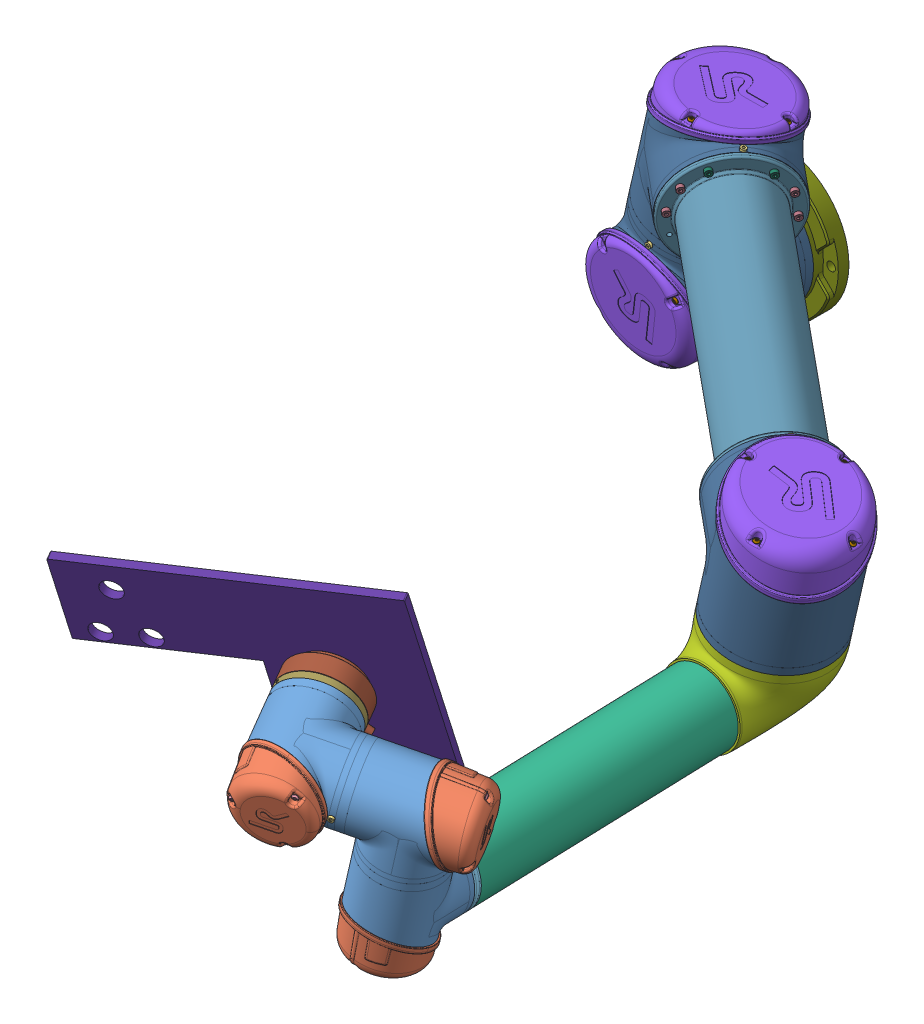
SolidWorks assembly 1-UR5-assembled, configuration Default. Lengths in mm.
75 component instances, 17 part files, 16 mates.
Components (placement in the parent):
- 1-Simple_Size 1_Joint_r01-1: 1-Simple_Size 1_Joint_r01 [默认] at (363.7688 30.1898 739.873) x (-0.221459 -0.97517 0) z (0.447518 -0.10163 0.888481) size (85.27 106.15 80.04)
  - 1-Size 1_House_r15_Simple-1: 1-Size 1_House_r15_Simple [默认] at origin size (82.75 89.23 75.23)
  - 1-Size 1_Joint lid_r08_Simple-1: 1-Size 1_Joint lid_r08_Simple [默认] at (0 -0.55 0) size (80.04 49.84 80.04)
  - 1-ISO 14580_M3x6_Torx_Rustfri A2_1-1: 1-ISO 14580_M3x6_Torx_Rustfri A2_1 [默认] at (42.25 40 0) x (0 -1 0) z (0 0 1) size (8.4 5.5 5.5)
  - 1-DIN 7985 Torx M3_DIN 7985 Torx M3 x 6 Syrefast-1: 1-DIN 7985 Torx M3_DIN 7985 Torx M3 x 6 Syrefast [默认] at (15.5 51.45 -26.8468) x (0 -1 0) z (0 0 1) size (7.97 5.77 5.75)
  - 1-DIN 7985 Torx M3_DIN 7985 Torx M3 x 6 Syrefast-2: 1-DIN 7985 Torx M3_DIN 7985 Torx M3 x 6 Syrefast [默认] at (15.5 51.45 26.8468) x (0 -1 0) z (0 0 1) size (7.97 5.77 5.75)
  - 1-DIN 7985 Torx M3_DIN 7985 Torx M3 x 6 Syrefast-3: 1-DIN 7985 Torx M3_DIN 7985 Torx M3 x 6 Syrefast [默认] at (-31 51.45 0) x (0 -1 0) z (0 0 1) size (7.97 5.77 5.75)
- 1-Simple_Size 1_Joint_r01-2: 1-Simple_Size 1_Joint_r01 [默认] at (281.6755 48.833 783.3551) x (0.86642 -0.196762 -0.458913) z (-0.290399 -0.946226 -0.142567) size (85.27 106.15 80.04)
  - 1-Size 1_House_r15_Simple-1: 1-Size 1_House_r15_Simple [默认] at origin size (82.75 89.23 75.23)
  - 1-Size 1_Joint lid_r08_Simple-1: 1-Size 1_Joint lid_r08_Simple [默认] at (0 -0.55 0) size (80.04 49.84 80.04)
  - 1-ISO 14580_M3x6_Torx_Rustfri A2_1-1: 1-ISO 14580_M3x6_Torx_Rustfri A2_1 [默认] at (42.25 40 0) x (0 -1 0) z (0 0 1) size (8.4 5.5 5.5)
  - 1-DIN 7985 Torx M3_DIN 7985 Torx M3 x 6 Syrefast-1: 1-DIN 7985 Torx M3_DIN 7985 Torx M3 x 6 Syrefast [默认] at (15.5 51.45 -26.8468) x (0 -1 0) z (0 0 1) size (7.97 5.77 5.75)
  - 1-DIN 7985 Torx M3_DIN 7985 Torx M3 x 6 Syrefast-2: 1-DIN 7985 Torx M3_DIN 7985 Torx M3 x 6 Syrefast [默认] at (15.5 51.45 26.8468) x (0 -1 0) z (0 0 1) size (7.97 5.77 5.75)
  - 1-DIN 7985 Torx M3_DIN 7985 Torx M3 x 6 Syrefast-3: 1-DIN 7985 Torx M3_DIN 7985 Torx M3 x 6 Syrefast [默认] at (-31 51.45 0) x (0 -1 0) z (0 0 1) size (7.97 5.77 5.75)
- 1-Simple_Underarm_r00-1: 1-Simple_Underarm_r00 [默认] at (332.2947 -59.8251 347.7706) x (-0.026745 0.006074 -0.999624) z (-0.974803 0.221376 0.027426) size (490.28 107.7 116.02)
  - 1-Adapter_Size 1 Tube to Female Size 1_r04_Simple-1: 1-Adapter_Size 1 Tube to Female Size 1_r04_Simple [默认] at (-345 0 0) x (-1 0 0) z (0 -0.876607 -0.481207) size (7 75 75)
  - 1-Simple_Size 1_Joint_r01-1: 1-Simple_Size 1_Joint_r01 [默认] at (-392.25 0 0) size (85.27 106.15 80.04)
    - 1-Size 1_House_r15_Simple-1: 1-Size 1_House_r15_Simple [默认] at origin size (82.75 89.23 75.23)
    - 1-Size 1_Joint lid_r08_Simple-1: 1-Size 1_Joint lid_r08_Simple [默认] at (0 -0.55 0) size (80.04 49.84 80.04)
    - 1-ISO 14580_M3x6_Torx_Rustfri A2_1-1: 1-ISO 14580_M3x6_Torx_Rustfri A2_1 [默认] at (42.25 40 0) x (0 -1 0) z (0 0 1) size (8.4 5.5 5.5)
    - 1-DIN 7985 Torx M3_DIN 7985 Torx M3 x 6 Syrefast-1: 1-DIN 7985 Torx M3_DIN 7985 Torx M3 x 6 Syrefast [默认] at (15.5 51.45 -26.8468) x (0 -1 0) z (0 0 1) size (7.97 5.77 5.75)
    - 1-DIN 7985 Torx M3_DIN 7985 Torx M3 x 6 Syrefast-2: 1-DIN 7985 Torx M3_DIN 7985 Torx M3 x 6 Syrefast [默认] at (15.5 51.45 26.8468) x (0 -1 0) z (0 0 1) size (7.97 5.77 5.75)
    - 1-DIN 7985 Torx M3_DIN 7985 Torx M3 x 6 Syrefast-3: 1-DIN 7985 Torx M3_DIN 7985 Torx M3 x 6 Syrefast [默认] at (-31 51.45 0) x (0 -1 0) z (0 0 1) size (7.97 5.77 5.75)
  - 1-Size 1 r鴕_r02_Simple-1: 1-Size 1 r鴕_r02_Simple [默认] at (-190.5 0 0) x (0 0.955999 0.29337) z (-1 0 0) size (75 75 274)
  - 1-Size 3 to Size 1_Angle_r03AB_Simple-1: 1-Size 3 to Size 1_Angle_r03AB_Simple [默认] at origin size (124.01 93.64 116.02)
- 1-Simple_Size 3_Joint_r00-1: 1-Simple_Size 3_Joint_r00 [默认] at (0 0 89.2) x (0 0 -1) z (-0.97517 0.221459 0) size (147.52 127.38 122.2)
  - 1-Size 3_Joint lid_r08_Simple-1: 1-Size 3_Joint lid_r08_Simple [默认] at origin size (71.68 122.21 122.2)
  - 1-ISO 14580_M3x6_Torx_Rustfri A2_1-1: 1-ISO 14580_M3x6_Torx_Rustfri A2_1 [默认] at (-60.65 -63.3 0) size (8.4 5.5 5.5)
  - 1-DIN 7985 Torx M3_DIN 7985 Torx M3 x 10 Syrefast-1: 1-DIN 7985 Torx M3_DIN 7985 Torx M3 x 10 Syrefast [默认] at (-61.87 -36.0624 -36.0624) size (11.97 5.77 5.75)
  - 1-DIN 7985 Torx M3_DIN 7985 Torx M3 x 10 Syrefast-2: 1-DIN 7985 Torx M3_DIN 7985 Torx M3 x 10 Syrefast [默认] at (-61.87 -36.0624 36.0624) size (11.97 5.77 5.75)
  - 1-DIN 7985 Torx M3_DIN 7985 Torx M3 x 10 Syrefast-3: 1-DIN 7985 Torx M3_DIN 7985 Torx M3 x 10 Syrefast [默认] at (-49.87 36.0624 36.0624) size (11.97 5.77 5.75)
  - 1-DIN 7985 Torx M3_DIN 7985 Torx M3 x 10 Syrefast-4: 1-DIN 7985 Torx M3_DIN 7985 Torx M3 x 10 Syrefast [默认] at (-49.87 36.0624 -36.0624) size (11.97 5.77 5.75)
  - 1-Size 3_House_r12_Simple-1: 1-Size 3_House_r12_Simple [默认] at origin size (127.69 124.3 116.38)
- 1-Simple_Size 1_Tool flange_r00-1: 1-Simple_Size 1_Tool flange_r00 [默认] at (261.9756 61.2873 740.8221) x (-0.406184 0.25679 -0.876968) z (-0.632904 -0.7713 0.067292) size (33 82 75)
  - 1-Size 1_Tool flange_r03AA_Simple-1: 1-Size 1_Tool flange_r03AA_Simple [默认] at (-0.5 0 0) size (26 82 75)
  - 1-Size 1_Tool flange temporary extension_r03AA_Simple-1: 1-Size 1_Tool flange temporary extension_r03AA_Simple [默认] at origin size (14 75 75)
- 1-Simple_Overarm_r00-1: 1-Simple_Overarm_r00 [默认] at (29.7198 130.8678 89.2) x (-0.221459 -0.97517 0) z (0.593295 -0.134736 -0.793629) size (147.52 547.17 122.21)
  - 1-ISO 4762_M4x20_Syrefast A4_ISO 4762 M4 x 20 --- 20N-1: 1-ISO 4762_M4x20_Syrefast A4_ISO 4762 M4 x 20 --- 20N [默认] at (24.75 -350.2 -42.8683) x (0 -1 0) z (0 0 1) size (24 7 7)
  - 1-ISO 4762_M4x20_Syrefast A4_ISO 4762 M4 x 20 --- 20N-2: 1-ISO 4762_M4x20_Syrefast A4_ISO 4762 M4 x 20 --- 20N [默认] at (0 -350.2 -49.5) x (0 -1 0) z (0.5 0 0.866025) size (24 7 7)
  - 1-Simple_Size 3_Joint_r00-1: 1-Simple_Size 3_Joint_r00 [默认] at origin size (147.52 127.38 122.2)
    - 1-Size 3_Joint lid_r08_Simple-1: 1-Size 3_Joint lid_r08_Simple [默认] at origin size (71.68 122.21 122.2)
    - 1-ISO 14580_M3x6_Torx_Rustfri A2_1-1: 1-ISO 14580_M3x6_Torx_Rustfri A2_1 [默认] at (-60.65 -63.3 0) size (8.4 5.5 5.5)
    - 1-DIN 7985 Torx M3_DIN 7985 Torx M3 x 10 Syrefast-1: 1-DIN 7985 Torx M3_DIN 7985 Torx M3 x 10 Syrefast [默认] at (-61.87 -36.0624 -36.0624) size (11.97 5.77 5.75)
    - 1-DIN 7985 Torx M3_DIN 7985 Torx M3 x 10 Syrefast-2: 1-DIN 7985 Torx M3_DIN 7985 Torx M3 x 10 Syrefast [默认] at (-61.87 -36.0624 36.0624) size (11.97 5.77 5.75)
    - 1-DIN 7985 Torx M3_DIN 7985 Torx M3 x 10 Syrefast-3: 1-DIN 7985 Torx M3_DIN 7985 Torx M3 x 10 Syrefast [默认] at (-49.87 36.0624 36.0624) size (11.97 5.77 5.75)
    - 1-DIN 7985 Torx M3_DIN 7985 Torx M3 x 10 Syrefast-4: 1-DIN 7985 Torx M3_DIN 7985 Torx M3 x 10 Syrefast [默认] at (-49.87 36.0624 -36.0624) size (11.97 5.77 5.75)
    - 1-Size 3_House_r12_Simple-1: 1-Size 3_House_r12_Simple [默认] at origin size (127.69 124.3 116.38)
  - 1-Link_Female Size 3 to Female Size 3_L284_r02AA_Simple-1: 1-Link_Female Size 3 to Female Size 3_L284_r02AA_Simple [默认] at (0 -212.5 0) x (0 -1 0) z (0 0 -1) size (292.4 115.5 115.5)
  - 1-ISO 4762_M4x16_Syrefast A4_ISO 4762 M4 x 16 --- 16N-1: 1-ISO 4762_M4x16_Syrefast A4_ISO 4762 M4 x 16 --- 16N [默认] at (42.8683 -350.2 24.75) x (0 -1 0) z (-0.866025 0 0.5) size (20 7 7)
  - 1-ISO 4762_M4x16_Syrefast A4_ISO 4762 M4 x 16 --- 16N-2: 1-ISO 4762_M4x16_Syrefast A4_ISO 4762 M4 x 16 --- 16N [默认] at (-42.8683 -350.2 -24.75) x (0 -1 0) z (0.866025 0 -0.5) size (20 7 7)
  - 1-ISO 4762_M4x20_Syrefast A4_ISO 4762 M4 x 20 --- 20N-3: 1-ISO 4762_M4x20_Syrefast A4_ISO 4762 M4 x 20 --- 20N [默认] at (24.75 -74.8 42.8683) x (0 1 0) z (-0.866025 0 -0.5) size (24 7 7)
  - 1-ISO 4762_M4x20_Syrefast A4_ISO 4762 M4 x 20 --- 20N-4: 1-ISO 4762_M4x20_Syrefast A4_ISO 4762 M4 x 20 --- 20N [默认] at (0 -74.8 49.5) x (0 1 0) z (-0.5 0 -0.866025) size (24 7 7)
  - 1-ISO 4762_M4x20_Syrefast A4_ISO 4762 M4 x 20 --- 20N-5: 1-ISO 4762_M4x20_Syrefast A4_ISO 4762 M4 x 20 --- 20N [默认] at (-24.75 -74.8 42.8683) x (0 1 0) z (0 0 -1) size (24 7 7)
  - 1-ISO 4762_M4x20_Syrefast A4_ISO 4762 M4 x 20 --- 20N-6: 1-ISO 4762_M4x20_Syrefast A4_ISO 4762 M4 x 20 --- 20N [默认] at (-24.75 -74.8 -42.8683) x (0 1 0) z (0.866025 0 0.5) size (24 7 7)
  - 1-ISO 4762_M4x20_Syrefast A4_ISO 4762 M4 x 20 --- 20N-7: 1-ISO 4762_M4x20_Syrefast A4_ISO 4762 M4 x 20 --- 20N [默认] at (0 -74.8 -49.5) x (0 1 0) z (0.5 0 0.866025) size (24 7 7)
  - 1-ISO 4762_M4x16_Syrefast A4_ISO 4762 M4 x 16 --- 16N-3: 1-ISO 4762_M4x16_Syrefast A4_ISO 4762 M4 x 16 --- 16N [默认] at (42.8683 -74.8 24.75) x (0 1 0) z (-0.866025 0 0.5) size (20 7 7)
  - 1-ISO 4762_M4x16_Syrefast A4_ISO 4762 M4 x 16 --- 16N-4: 1-ISO 4762_M4x16_Syrefast A4_ISO 4762 M4 x 16 --- 16N [默认] at (-42.8683 -74.8 24.75) x (0 1 0) z (0 0 -1) size (20 7 7)
  - 1-ISO 4762_M4x16_Syrefast A4_ISO 4762 M4 x 16 --- 16N-5: 1-ISO 4762_M4x16_Syrefast A4_ISO 4762 M4 x 16 --- 16N [默认] at (-42.8683 -74.8 -24.75) x (0 1 0) z (0.866025 0 -0.5) size (20 7 7)
  - 1-ISO 4762_M4x16_Syrefast A4_ISO 4762 M4 x 16 --- 16N-6: 1-ISO 4762_M4x16_Syrefast A4_ISO 4762 M4 x 16 --- 16N [默认] at (42.8683 -74.8 -24.75) x (0 1 0) z (0 0 1) size (20 7 7)
  - 1-ISO 4762_M4x20_Syrefast A4_ISO 4762 M4 x 20 --- 20N-8: 1-ISO 4762_M4x20_Syrefast A4_ISO 4762 M4 x 20 --- 20N [默认] at (24.75 -350.2 42.8683) x (0 -1 0) z (-0.866025 0 -0.5) size (24 7 7)
  - 1-ISO 4762_M4x20_Syrefast A4_ISO 4762 M4 x 20 --- 20N-9: 1-ISO 4762_M4x20_Syrefast A4_ISO 4762 M4 x 20 --- 20N [默认] at (0 -350.2 49.5) x (0 -1 0) z (-0.5 0 -0.866025) size (24 7 7)
  - 1-Simple_Size 3_Joint_r00-2: 1-Simple_Size 3_Joint_r00 [默认] at (0 -425 0) x (1 0 0) z (0 0 -1) size (147.52 127.38 122.2)
    - 1-Size 3_Joint lid_r08_Simple-1: 1-Size 3_Joint lid_r08_Simple [默认] at origin size (71.68 122.21 122.2)
    - 1-ISO 14580_M3x6_Torx_Rustfri A2_1-1: 1-ISO 14580_M3x6_Torx_Rustfri A2_1 [默认] at (-60.65 -63.3 0) size (8.4 5.5 5.5)
    - 1-DIN 7985 Torx M3_DIN 7985 Torx M3 x 10 Syrefast-1: 1-DIN 7985 Torx M3_DIN 7985 Torx M3 x 10 Syrefast [默认] at (-61.87 -36.0624 -36.0624) size (11.97 5.77 5.75)
    - 1-DIN 7985 Torx M3_DIN 7985 Torx M3 x 10 Syrefast-2: 1-DIN 7985 Torx M3_DIN 7985 Torx M3 x 10 Syrefast [默认] at (-61.87 -36.0624 36.0624) size (11.97 5.77 5.75)
    - 1-DIN 7985 Torx M3_DIN 7985 Torx M3 x 10 Syrefast-3: 1-DIN 7985 Torx M3_DIN 7985 Torx M3 x 10 Syrefast [默认] at (-49.87 36.0624 36.0624) size (11.97 5.77 5.75)
    - 1-DIN 7985 Torx M3_DIN 7985 Torx M3 x 10 Syrefast-4: 1-DIN 7985 Torx M3_DIN 7985 Torx M3 x 10 Syrefast [默认] at (-49.87 36.0624 -36.0624) size (11.97 5.77 5.75)
    - 1-Size 3_House_r12_Simple-1: 1-Size 3_House_r12_Simple [默认] at origin size (127.69 124.3 116.38)
  - 1-ISO 4762_M4x20_Syrefast A4_ISO 4762 M4 x 20 --- 20N-10: 1-ISO 4762_M4x20_Syrefast A4_ISO 4762 M4 x 20 --- 20N [默认] at (-24.75 -350.2 42.8683) x (0 -1 0) z (0 0 -1) size (24 7 7)
  - 1-ISO 4762_M4x16_Syrefast A4_ISO 4762 M4 x 16 --- 16N-7: 1-ISO 4762_M4x16_Syrefast A4_ISO 4762 M4 x 16 --- 16N [默认] at (-42.8683 -350.2 24.75) x (0 -1 0) z (0 0 -1) size (20 7 7)
  - 1-ISO 4762_M4x16_Syrefast A4_ISO 4762 M4 x 16 --- 16N-8: 1-ISO 4762_M4x16_Syrefast A4_ISO 4762 M4 x 16 --- 16N [默认] at (42.8683 -350.2 -24.75) x (0 -1 0) z (0 0 1) size (20 7 7)
  - 1-ISO 4762_M4x20_Syrefast A4_ISO 4762 M4 x 20 --- 20N-11: 1-ISO 4762_M4x20_Syrefast A4_ISO 4762 M4 x 20 --- 20N [默认] at (-24.75 -350.2 -42.8683) x (0 -1 0) z (0.866025 0 0.5) size (24 7 7)
- 1-Size 3_Round base_r04_Simple-1: 1-Size 3_Round base_r04_Simple [默认] at (0 0 3) x (0 0 -1) z (0 -1 0) size (21.3 147 147)
- 零件8-1: 零件8 [默认] at (3733.786 -3390.0421 -1925.7083) x (-0.018541 0.957189 0.288868) z (0.406184 -0.25679 0.876968) size (192.44 286.01 8)
Mates (geometry in assembly coordinates):
- 重合1: coincident anti-aligned: plane of 1-Simple_Size 3_Joint_r00-1/1-Size 3_House_r12_Simple-1 through (0 0 21.3) normal (0 0 -1); plane of 1-Size 3_Round base_r04_Simple-1 through (56.1 0 21.3) normal (0 0 1)
- 同心1: concentric aligned: cylinder of 1-Simple_Size 3_Joint_r00-1/1-Size 3_House_r12_Simple-1 through (0 0 21.3) axis (0 0 1) radius 58; cylinder of 1-Size 3_Round base_r04_Simple-1 through (0 0 0) axis (0 0 1) radius 58
- 重合2: coincident anti-aligned: plane of 1-Simple_Size 3_Joint_r00-1/1-Size 3_House_r12_Simple-1 through (16.7999 64.1362 89.2) normal (0.253392 0.967364 0); plane of ? through (16.7999 64.1362 89.2) normal (-0.253392 -0.967364 0)
- 同心2: concentric anti-aligned: cylinder of 1-Simple_Size 3_Joint_r00-1/1-Size 3_House_r12_Simple-1 through (17.0533 65.1036 89.2) axis (-0.253392 -0.967364 0) radius 58; cylinder of ? through (16.7999 64.1362 89.2) axis (0.253392 0.967364 0) radius 58
- 重合3: coincident anti-aligned: plane of 1-Simple_Underarm_r00-1/1-Size 3 to Size 1_Angle_r03AB_Simple-1; plane of ?
- 同心3: concentric anti-aligned: cylinder of 1-Simple_Underarm_r00-1/1-Size 3 to Size 1_Angle_r03AB_Simple-1 through (348.2308 -28.4165 338.6863) axis (-0.253392 -0.967364 0) radius 58; cylinder of ? through (349.6371 -23.0476 338.6863) axis (0.253392 0.967364 0) radius 58
- 重合4: coincident anti-aligned: plane of 1-Simple_Size 1_Joint_r01-1/1-Size 1_House_r15_Simple-1; plane of ?
- 同心4: concentric anti-aligned: cylinder of 1-Simple_Size 1_Joint_r01-1/1-Size 1_House_r15_Simple-1 through (461.537 -54.9948 713.2852) axis (0.253392 0.967364 0) radius 37.5; cylinder of ? through (461.7904 -54.0275 713.2852) axis (-0.253392 -0.967364 0) radius 37.5
- 重合5: coincident anti-aligned: plane of 1-Simple_Size 1_Joint_r01-1/1-Size 1_House_r15_Simple-1; plane of 1-Simple_Size 1_Joint_r01-2/1-Size 1_House_r15_Simple-1
- 同心5: concentric anti-aligned: cylinder of 1-Simple_Size 1_Joint_r01-1/1-Size 1_House_r15_Simple-1 through (446.3673 -3.2109 754.2439) axis (0.543214 -0.14229 -0.827449) radius 37.5; cylinder of 1-Simple_Size 1_Joint_r01-2/1-Size 1_House_r15_Simple-1 through (446.9105 -3.3532 753.4165) axis (-0.543214 0.14229 0.827449) radius 37.5
- 重合6: coincident anti-aligned: plane of 1-Simple_Size 1_Joint_r01-2/1-Size 1_House_r15_Simple-1; plane of 1-Simple_Size 1_Tool flange_r00-1/1-Size 1_Tool flange temporary extension_r03AA_Simple-1
- 同心6: concentric aligned: cylinder of 1-Simple_Size 1_Joint_r01-2/1-Size 1_House_r15_Simple-1 through (380.4071 3.2277 764.5206) axis (0.835955 0 0.548798) radius 37.5; cylinder of 1-Simple_Size 1_Tool flange_r00-1/1-Size 1_Tool flange temporary extension_r03AA_Simple-1 through (381.2431 3.2277 765.0694) axis (0.835955 0 0.548798) radius 37.5
- 重合7: coincident: plane of 1-Simple_Size 1_Tool flange_r00-1/1-Size 1_Tool flange_r03AA_Simple-1; plane of 零件8-1
- 同心7: concentric: cylinder of 1-Simple_Size 1_Tool flange_r00-1/1-Size 1_Tool flange_r03AA_Simple-1 through (381.6611 3.2277 765.3438) axis (0.835955 0 0.548798) radius 15.75; cylinder of 零件8-1 through (352.8206 3.2277 746.4102) axis (-0.835955 0 -0.548798) radius 14.2377
- 同心8: concentric: cylinder of 1-Simple_Size 1_Tool flange_r00-1/1-Size 1_Tool flange_r03AA_Simple-1 through (418359.6383 28.2203 275163.6137) axis (-0.835955 0 -0.548798) radius 2.46; cylinder of 零件8-1 through (346.4684 28.2203 741.5089) axis (0.835955 0 0.548798) radius 2.7197
- 同心9: concentric anti-aligned: cylinder of 1-Simple_Size 1_Tool flange_r00-1/1-Size 1_Tool flange_r03AA_Simple-1 through (418373.0187 2.6165 275143.232) axis (-0.835955 0 -0.548798) radius 2.46; cylinder of 零件8-1 through (359.8488 2.6165 721.1272) axis (0.835955 0 0.548798) radius 3.0863
